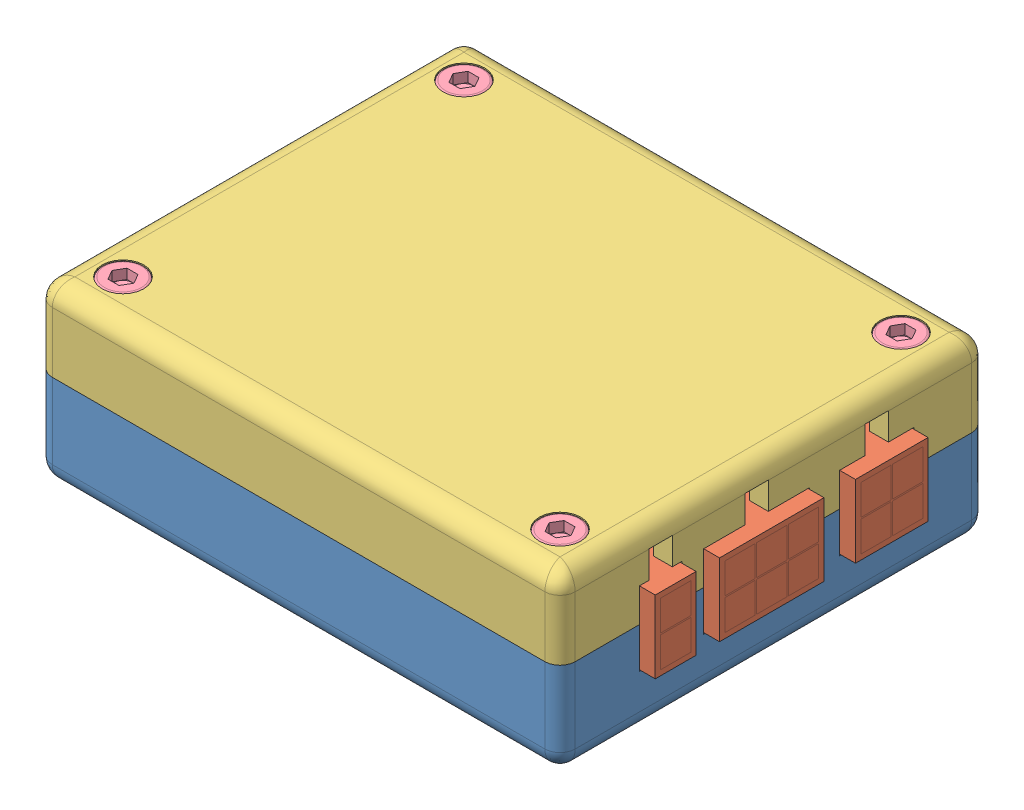
SolidWorks assembly Housing, configuration Standard. Lengths in mm.
Overall size (73.14 23 56.44).
11 component instances, 5 part files, 29 mates.
Components (placement in the parent):
- Housing-Bottom-1: Housing-Bottom [Standard] at (-69.135 0 56.435) size (69.14 12.5 56.44)
- Audio-Switch-1: Audio-Switch [Standard] at (-66.635 6.3 53.935) x (1 0 0) z (0 1 0) size (73.14 51.44 13.69)
- Housing-Top-1: Housing-Top [Standard] at (-69.135 20.5 56.435) size (69.14 15.9 56.44)
- socket head cap screw_din-1: socket head cap screw_din [DIN 912 M3 x 20 --- 20S] at (-5.675 23 50.76) x (0 -1 0) z (0 0 1) size (23 5.5 5.5)
- socket head cap screw_din-2: socket head cap screw_din [DIN 912 M3 x 20 --- 20S] at (-63.46 23 5.675) x (0 -1 0) z (0 0 1) size (23 5.5 5.5)
- socket head cap screw_din-3: socket head cap screw_din [DIN 912 M3 x 20 --- 20S] at (-63.46 23 50.76) x (0 -1 0) z (0 0 1) size (23 5.5 5.5)
- socket head cap screw_din-4: socket head cap screw_din [DIN 912 M3 x 20 --- 20S] at (-5.675 23 5.675) x (0 -1 0) z (0 0 1) size (23 5.5 5.5)
- hex thin nut chamfered gradeab_din-1: hex thin nut chamfered gradeab_din [Hexagon Thin Nut ISO 4035 - M3 - S] at (-63.46 2 50.76) x (1 0 0) z (0 1 0) size (5.5 6.35 1.8)
- hex thin nut chamfered gradeab_din-2: hex thin nut chamfered gradeab_din [Hexagon Thin Nut ISO 4035 - M3 - S] at (-63.46 2 5.675) x (1 0 0) z (0 1 0) size (5.5 6.35 1.8)
- hex thin nut chamfered gradeab_din-3: hex thin nut chamfered gradeab_din [Hexagon Thin Nut ISO 4035 - M3 - S] at (-5.675 2 5.675) x (1 0 0) z (0 1 0) size (5.5 6.35 1.8)
- hex thin nut chamfered gradeab_din-4: hex thin nut chamfered gradeab_din [Hexagon Thin Nut ISO 4035 - M3 - S] at (-5.675 2 50.76) x (1 0 0) z (0 1 0) size (5.5 6.35 1.8)
Mates (geometry in assembly coordinates):
- Deckungsgleich2: coincident: plane of Housing-Bottom-1 through (-66.635 12.5 53.935) normal (0 0 -1); plane of Audio-Switch-1 through (-2.5 5.5 53.935) normal (0 0 1)
- Deckungsgleich3: coincident: plane of Housing-Bottom-1 through (-66.635 12.5 53.935) normal (1 0 0); plane of Audio-Switch-1 through (-66.635 5.5 53.935) normal (-1 0 0)
- Deckungsgleich4: coincident anti-aligned: plane of Housing-Bottom-1 through (-63.46 5.5 50.76) normal (0 1 0); plane of Audio-Switch-1 through (-66.635 5.5 53.935) normal (0 -1 0)
- Deckungsgleich5: coincident anti-aligned: plane of Housing-Bottom-1 through (-67.135 12.5 2) normal (0 1 0); plane of Housing-Top-1 through (-69.135 12.5 56.435) normal (0 -1 0)
- Deckungsgleich6: coincident aligned: plane of Housing-Bottom-1 through (-69.135 2.5 54.435) normal (-1 0 0); plane of Housing-Top-1 through (-69.135 23 54.435) normal (-1 0 0)
- Deckungsgleich7: coincident aligned: plane of Housing-Bottom-1 through (-67.135 2.5 56.435) normal (0 0 1); plane of Housing-Top-1 through (-67.135 23 56.435) normal (0 0 1)
- Deckungsgleich8: coincident anti-aligned: plane of Housing-Top-1 through (-63.46 20 5.675) normal (0 1 0); plane of socket head cap screw_din-2 through (-60.71 20 5.675) normal (0 -1 0)
- Deckungsgleich9: coincident anti-aligned: plane of Housing-Top-1 through (-63.46 20 50.76) normal (0 1 0); plane of socket head cap screw_din-3 through (-60.71 20 50.76) normal (0 -1 0)
- Deckungsgleich10: coincident anti-aligned: plane of Housing-Top-1 through (-5.675 20 5.675) normal (0 1 0); plane of socket head cap screw_din-4 through (-2.925 20 5.675) normal (0 -1 0)
- Deckungsgleich11: coincident anti-aligned: plane of Housing-Top-1 through (-5.675 20 50.76) normal (0 1 0); plane of socket head cap screw_din-1 through (-2.925 20 50.76) normal (0 -1 0)
- Konzentrisch1: concentric anti-aligned: cylinder of Housing-Top-1 through (-63.46 23 5.675) axis (0 -1 0) radius 1.5; cylinder of socket head cap screw_din-2 through (-63.46 54.75 5.675) axis (0 1 0) radius 1.5
- Konzentrisch2: concentric anti-aligned: cylinder of Housing-Top-1 through (-63.46 23 50.76) axis (0 -1 0) radius 1.5; cylinder of socket head cap screw_din-3 through (-63.46 54.75 50.76) axis (0 1 0) radius 1.5
- Konzentrisch3: concentric anti-aligned: cylinder of Housing-Top-1 through (-5.675 23 5.675) axis (0 -1 0) radius 1.5; cylinder of socket head cap screw_din-4 through (-5.675 54.75 5.675) axis (0 1 0) radius 1.5
- Konzentrisch4: concentric anti-aligned: cylinder of Housing-Top-1 through (-5.675 23 50.76) axis (0 -1 0) radius 1.5; cylinder of socket head cap screw_din-1 through (-5.675 54.75 50.76) axis (0 1 0) radius 1.5
- Deckungsgleich12: coincident anti-aligned: plane of Housing-Bottom-1 through (-69.135 2 56.435) normal (0 -1 0); plane of hex thin nut chamfered gradeab_din-4 through (-5.675 2 47.5846) normal (0 1 0)
- Deckungsgleich13: coincident anti-aligned: plane of Housing-Bottom-1 through (-69.135 2 56.435) normal (0 -1 0); plane of hex thin nut chamfered gradeab_din-3 through (-5.675 2 2.4996) normal (0 1 0)
- Deckungsgleich15: coincident anti-aligned: plane of Housing-Bottom-1 through (-69.135 2 56.435) normal (0 -1 0); plane of hex thin nut chamfered gradeab_din-1 through (-63.46 2 47.5846) normal (0 1 0)
- Deckungsgleich16: coincident anti-aligned: plane of Housing-Bottom-1 through (-69.135 2 56.435) normal (0 -1 0); plane of hex thin nut chamfered gradeab_din-2 through (-63.46 2 2.4996) normal (0 1 0)
- Deckungsgleich17: coincident anti-aligned: plane of Housing-Bottom-1 through (-2.925 2 49.1723) normal (-1 0 0); plane of hex thin nut chamfered gradeab_din-4 through (-2.925 0.2 49.1723) normal (1 0 0)
- Deckungsgleich18: coincident anti-aligned: plane of Housing-Bottom-1 through (-2.925 2 52.3477) normal (-0.5 0 -0.866025); plane of hex thin nut chamfered gradeab_din-4 through (-5.675 0.2 53.9354) normal (0.5 0 0.866025)
- Deckungsgleich19: coincident anti-aligned: plane of Housing-Bottom-1 through (-5.675 2 2.4996) normal (-0.5 0 0.866025); plane of hex thin nut chamfered gradeab_din-3 through (-2.925 0.2 4.0873) normal (0.5 0 -0.866025)
- Deckungsgleich20: coincident anti-aligned: plane of Housing-Bottom-1 through (-8.425 2 4.0873) normal (0.5 0 0.866025); plane of hex thin nut chamfered gradeab_din-3 through (-5.675 0.2 2.4996) normal (-0.5 0 -0.866025)
- Deckungsgleich21: coincident anti-aligned: plane of Housing-Bottom-1 through (-63.46 2 47.5846) normal (-0.5 0 0.866025); plane of hex thin nut chamfered gradeab_din-1 through (-60.71 0.2 49.1723) normal (0.5 0 -0.866025)
- Deckungsgleich22: coincident anti-aligned: plane of Housing-Bottom-1 through (-60.71 2 49.1723) normal (-1 0 0); plane of hex thin nut chamfered gradeab_din-1 through (-60.71 0.2 49.1723) normal (1 0 0)
- Deckungsgleich23: coincident anti-aligned: plane of Housing-Bottom-1 through (-60.71 2 7.2627) normal (-0.5 0 -0.866025); plane of hex thin nut chamfered gradeab_din-2 through (-63.46 0.2 8.8504) normal (0.5 0 0.866025)
- Deckungsgleich24: coincident anti-aligned: plane of Housing-Bottom-1 through (-60.71 2 4.0873) normal (-1 0 0); plane of hex thin nut chamfered gradeab_din-2 through (-60.71 0.2 4.0873) normal (1 0 0)
- Deckungsgleich25: coincident anti-aligned: plane of Housing-Bottom-1 through (-2 0 54.435) normal (0 -1 0); plane of assembly through (0 0 0) normal (0 1 0)
- Deckungsgleich26: coincident anti-aligned: plane of Housing-Bottom-1 through (-67.135 2.5 0) normal (0 0 -1); plane of assembly through (0 0 0) normal (0 0 1)
- Deckungsgleich27: coincident aligned: plane of Housing-Bottom-1 through (0 2.5 54.435) normal (1 0 0); plane of assembly through (0 0 0) normal (1 0 0)
